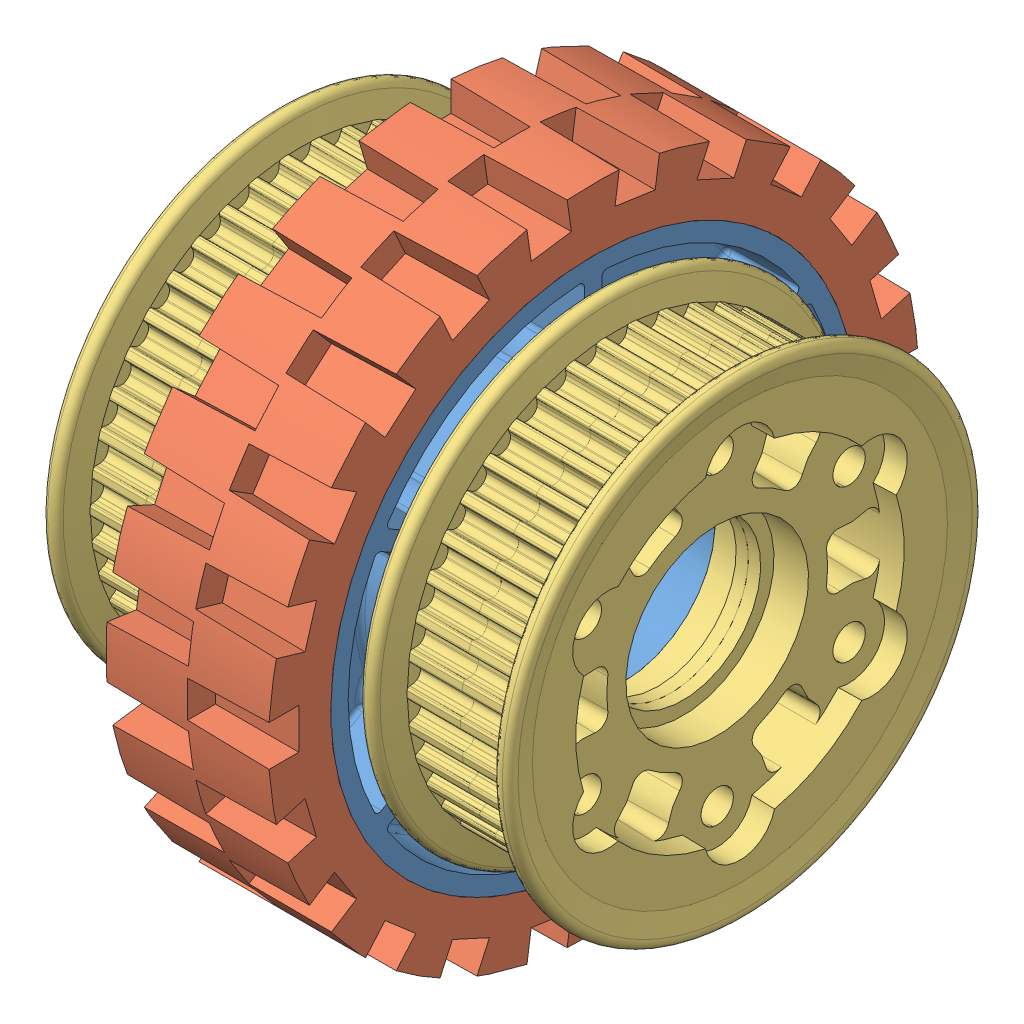
SolidWorks assembly 2014 KoP - 4 HiGrip and Double 42 HTD Pulley, configuration Default. Lengths in mm.
Overall size (73.17 101.6 101.6).
11 component instances, 4 part files, 7 mates.
Components (placement in the parent):
- 4 in HiGrip Wheel-2: 4 in HiGrip Wheel [Default] at (-22.4654 3.231 9.6596) size (34.92 101.6 101.6)
  - 4in 2013 Hub-1: 4in 2013 Hub [Default] at (-8.0517 2.5236 2.5343) size (34.92 82.55 82.55)
  - 4 in tread-1: 4 in tread [Default] at (-8.0517 2.5236 2.5343) size (25.4 101.6 101.6)
- 42 HTD Pulley 500 Hex Hub-1: 42 HTD Pulley 500 Hex Hub [Default] at (-50.7937 -35.9658 -59.7569) size (25.4 78.07 78.07)
  - 42 - 2014 tooth pulley assembly-1: 42 - 2014 tooth pulley assembly [Default] at (-12.8322 41.7203 71.9507) size (23.46 74.23 74.23)
    - 42 tooth HTD Pulley half 2014-1: 42 tooth HTD Pulley half 2014 [Default] at origin size (13 74.23 74.23)
    - 42 tooth HTD Pulley half 2014-2: 42 tooth HTD Pulley half 2014 [Default] at (16.6624 0 0) x (-1 0 0) z (0 0.000084 1) size (13 74.23 74.23)
  - 500 Hex Hub-1: 500 Hex Hub [Default] at (1.2188 41.7203 71.9507) x (1 0 0) z (0 0.500018 0.866015) size (25.4 57.15 57.15)
- 42 - 2014 tooth pulley assembly-1: 42 - 2014 tooth pulley assembly [Default] at (-14.0706 5.7546 12.1939) size (23.46 74.23 74.23)
  - 42 tooth HTD Pulley half 2014-1: 42 tooth HTD Pulley half 2014 [Default] at origin size (13 74.23 74.23)
  - 42 tooth HTD Pulley half 2014-2: 42 tooth HTD Pulley half 2014 [Default] at (16.6624 0 0) x (-1 0 0) z (0 0.000084 1) size (13 74.23 74.23)
Mates (geometry in assembly coordinates):
- Concentric8: concentric: cylinder of ? through (-47.9796 17.6608 -8.4284) axis (1 0 0) radius 1.9939; cylinder of ? through (-47.9796 17.6608 -8.4284) axis (1 0 0) radius 2.159
- Concentric13: concentric anti-aligned: cylinder of ? through (-47.9796 17.6608 32.8161) axis (1 0 0) radius 1.9939; cylinder of ? through (0.9144 17.6608 32.8161) axis (-1 0 0) radius 2.413
- Concentric15: concentric aligned: cylinder of ? through (-47.9796 17.6608 32.8161) axis (1 0 0) radius 1.9939; cylinder of ? through (-67.695 17.6608 32.8161) axis (1 0 0) radius 5.2578
- Concentric16: concentric aligned: cylinder of ? through (-20.0396 5.7546 12.1939) axis (1 0 0) radius 14.2875; cylinder of 42 - 2014 tooth pulley assembly-1/42 tooth HTD Pulley half 2014-2 through (-3.8217 5.7546 12.1939) axis (1 0 0) radius 14.2875
- Coincident1: coincident anti-aligned: plane of ? through (-13.0546 5.7546 12.1939) normal (1 0 0); plane of 42 - 2014 tooth pulley assembly-1/42 tooth HTD Pulley half 2014-1 through (-13.0546 5.7546 12.1939) normal (-1 0 0)
- Concentric17: concentric aligned: cylinder of ? through (-40.9946 5.7546 12.1939) axis (-1 0 0) radius 14.2875; cylinder of 42 HTD Pulley 500 Hex Hub-1/500 Hex Hub-1 through (-41.782 5.7546 12.1939) axis (-1 0 0) radius 12.1666
- Coincident2: coincident anti-aligned: plane of ? through (-47.9796 5.7546 12.1939) normal (-1 0 0); plane of 42 HTD Pulley 500 Hex Hub-1/42 - 2014 tooth pulley assembly-1/42 tooth HTD Pulley half 2014-2 through (-47.9796 5.7546 12.1939) normal (1 0 0)
